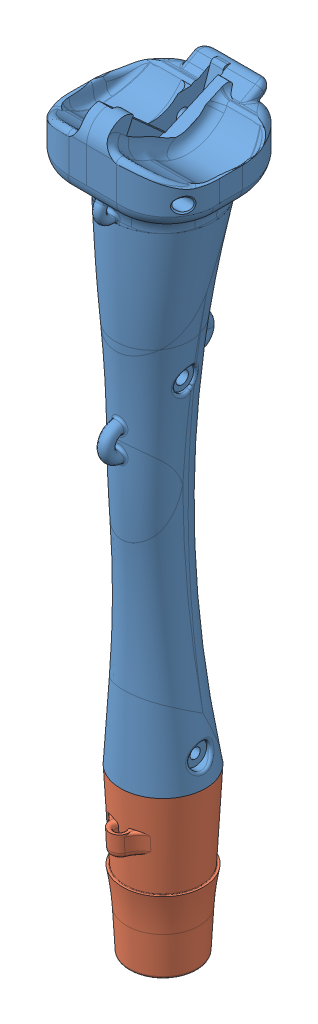
SolidWorks assembly Assem - test, configuration Default. Lengths in mm.
Overall size (75.42 378.01 77.35).
2 component instances, 2 part files, 3 mates.
Components (placement in the parent):
- Tibial head with hardware - bone connection - test-1: Tibial head with hardware - bone connection - test [Default] at origin size (75.42 296.73 77.35)
- Tibial End-1: Tibial End [Default] at (-44.0222 -418.6678 51.9742) size (42.45 113.08 48.21)
Mates (geometry in assembly coordinates):
- Coincident1: coincident anti-aligned: plane of Tibial head with hardware - bone connection - test-1 through (-44.0222 -317.0678 51.9742) normal (0 -1 0); plane of Tibial End-1 through (-44.0222 -317.0678 51.9742) normal (0 1 0)
- Coincident2: coincident anti-aligned: plane of Tibial head with hardware - bone connection - test-1 through (-34.4972 -278.9678 61.4992) normal (-1 0 0); plane of Tibial End-1 through (-34.4972 -285.3178 61.4992) normal (1 0 0)
- Coincident3: coincident anti-aligned: plane of Tibial head with hardware - bone connection - test-1 through (-34.4972 -278.9678 61.4992) normal (0 0 -1); plane of Tibial End-1 through (-34.4972 -285.3178 61.4992) normal (0 0 1)
